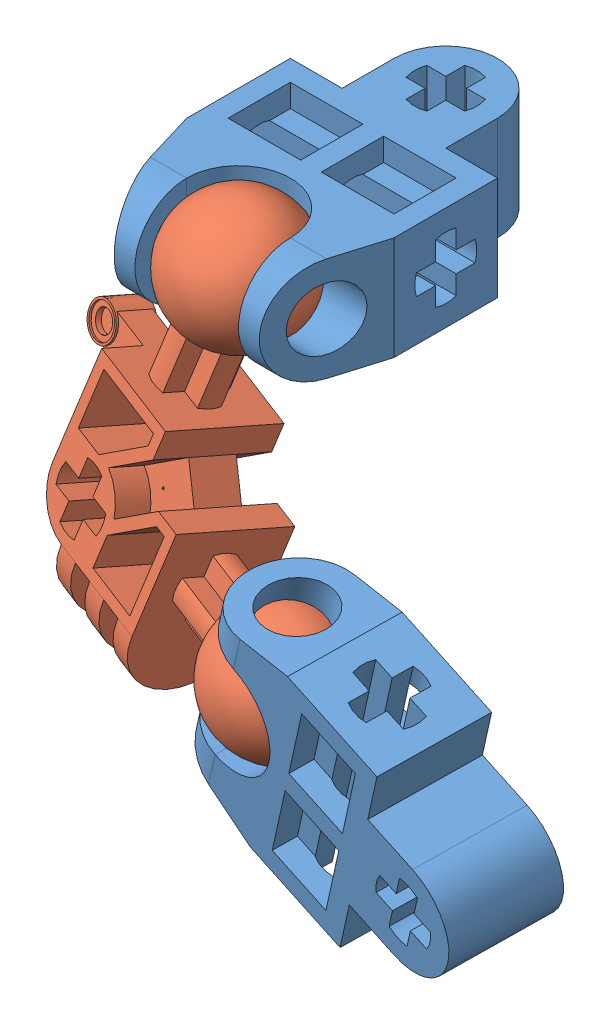
SolidWorks assembly Assem1, configuration Default. Lengths in mm.
Overall size (29.66 24.64 22.3).
3 component instances, 2 part files, 2 mates.
Components (placement in the parent):
- the hand-1: the hand [Default] at (10.731 4.297 11.2045) size (10 5 15)
- the hand-2: the hand [Default] at (20.5726 -4.8145 16.5408) x (-0.314677 -0.93929 -0.136791) z (-0.941762 0.326957 -0.078636) size (10 5 15)
- link 2x2-1: link 2x2 [Default] at (8.4252 -2.624 16.1391) x (0.230579 0.942105 -0.243457) z (0.949649 -0.163331 0.267374) size (17.5 6 18.1)
Mates (geometry in assembly coordinates):
- Concentric1: concentric: sphere of the hand-1; sphere of link 2x2-1
- Concentric2: concentric: sphere of the hand-2; sphere of link 2x2-1
